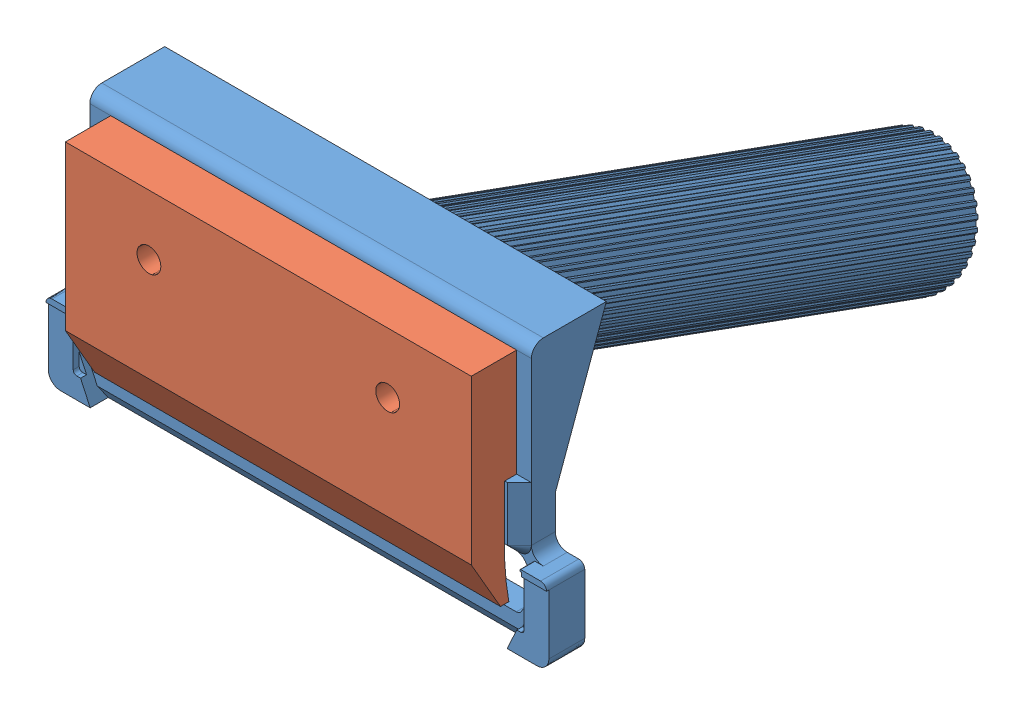
SolidWorks assembly Assem1, configuration Default. Lengths in mm.
Overall size (41.93 29.63 56.02).
2 component instances, 2 part files, 3 mates.
Components (placement in the parent):
- final part1-1: final part1 [Default] at (8.1015 24.8814 70.4433) size (41.93 29.63 53.42)
- final part2-1: final part2 [Default] at (8.359 36.9359 73.4433) size (34 17.93 3.8)
Mates (geometry in assembly coordinates):
- Coincident2: coincident anti-aligned: plane of final part1-1 through (39.9144 36.9359 72.4433) normal (0 0 1); plane of final part2-1 through (-8.641 36.9359 72.4433) normal (0 0 -1)
- Coincident3: coincident anti-aligned: plane of final part1-1 through (8.1015 36.9359 72.4433) normal (0 1 0); plane of final part2-1 through (-8.641 36.9359 73.4433) normal (0 -1 0)
- Parallel1: parallel anti-aligned: cylinder of final part1-1 through (-1.8985 40.8814 58.4433) axis (0 0 1) radius 1; cylinder of final part2-1 through (-1.641 40.8859 89.4433) axis (0 0 -1) radius 1
